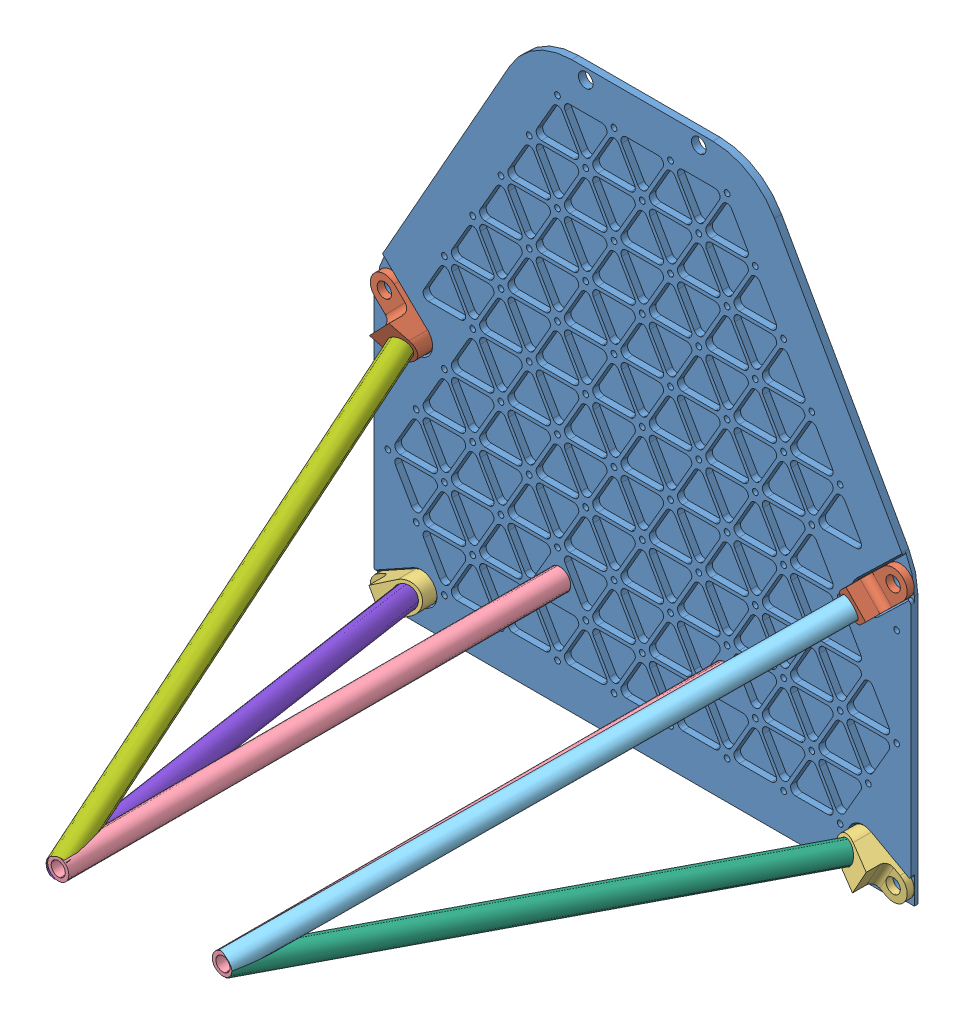
SolidWorks assembly Concept2_Simulation, configuration Default. Lengths in mm.
Overall size (493.12 512.57 459.07).
11 component instances, 8 part files, 30 mates.
Components (placement in the parent):
- Backplane_Simplifed-1: Backplane_Simplifed [Default] x (0 0 1) z (-1 0 0) size (6.35 508 482.6)
- Upper_Support_Mount-1: Upper_Support_Mount [Default] at (223.0175 237.3105 0) x (0.694489 -0.719504 0) z (-0.719504 -0.694489 0) size (25.4 25.4 61.27)
- Upper_Support_Mount-3: Upper_Support_Mount [Default] at (-205.3775 255.5859 0) x (0.694489 0.719504 0) z (0.719504 -0.694489 0) size (25.4 25.4 61.27)
- Lower_Support_Mount-1: Lower_Support_Mount [Default] at (223.4404 42.7827 0) x (-0.874551 0.484934 0) z (0 0 1) size (59.69 25.4 25.4)
- Chassis_Tube_1R-1: Chassis_Tube_1R [Default] at (0 111.125 -3.175) size (19.05 19.05 457.2)
- Chassis_Tube_2R-1: Chassis_Tube_2R [Default] at (0 111.125 -3.175) size (147.14 136.3 452.73)
- Chassis_Tube_3R-1: Chassis_Tube_3R [Default] at (0 111.125 -3.175) size (141.04 83.64 452.31)
- Chassis_Tube_1R-3: Chassis_Tube_1R [Default] at (-148 111.125 -3.175) size (19.05 19.05 457.2)
- Chassis_Tube_2L-1: Chassis_Tube_2L [Default] at (0 111.125 -3.175) size (147.14 136.3 452.73)
- Chassis_Tube_3L-1: Chassis_Tube_3L [Default] at (0 111.125 -3.175) size (141.04 85.18 452.31)
- Lower_Support_Mount-2: Lower_Support_Mount [Default] at (-211.1231 20.5691 0) x (0.874551 0.484934 0) z (0 0 1) size (59.69 25.4 25.4)
Mates (geometry in assembly coordinates):
- Coincident1: coincident aligned: plane of Backplane_Simplifed-1 through (0 0 0) normal (0 0 1)
- Coincident2: coincident anti-aligned: plane of Backplane_Simplifed-1 through (0 0 0) normal (-1 0 0)
- Coincident3: coincident aligned: plane of Backplane_Simplifed-1 through (0 0 0) normal (0 1 0)
- Concentric4: concentric anti-aligned: cylinder of Backplane_Simplifed-1 through (228.6 260.35 3.175) axis (0 0 -1) radius 6.5484; cylinder of Upper_Support_Mount-1 through (228.6 260.35 -6.7797) axis (0 0 1) radius 6.5484
- Parallel2: parallel anti-aligned: plane of Backplane_Simplifed-1 through (251.9603 264.9713 0) normal (-0.694489 0.719504 0); plane of Upper_Support_Mount-1 through (44.5113 65.0105 -3.175) normal (0.694489 -0.719504 0)
- Concentric5: concentric anti-aligned: cylinder of Backplane_Simplifed-1 through (228.6 25.4 3.175) axis (0 0 -1) radius 6.5484; cylinder of Lower_Support_Mount-1 through (228.6 25.4 -6.1235) axis (0 0 1) radius 6.5484
- Parallel3: parallel anti-aligned: plane of Backplane_Simplifed-1 through (204.8666 53.3087 0) normal (-0.484934 -0.874551 0); plane of Lower_Support_Mount-1 through (23.5606 153.6152 -3.175) normal (0.484934 0.874551 0)
- Concentric6: concentric anti-aligned: cylinder of Backplane_Simplifed-1 through (74 111.125 0) axis (0 0 1) radius 9.7234; cylinder of Chassis_Tube_1-1 through (74 111.125 454.025) axis (0 0 -1) radius 9.525
- Coincident8: coincident aligned: plane of Backplane_Simplifed-1 through (0 0 -3.175) normal (0 0 -1); plane of Chassis_Tube_1-1 through (74 111.125 -3.175) normal (0 0 -1)
- Concentric10: concentric anti-aligned: cylinder of Upper_Support_Mount-1 through (205.5695 238.1202 6.7766) axis (-0.272295 -0.262828 0.925622) radius 9.7234; cylinder of Chassis_Tube_2-1 through (74 111.125 454.025) axis (0.272295 0.262828 -0.925622) radius 9.525
- Coincident10: coincident anti-aligned: plane of Upper_Support_Mount-1 through (205.5695 238.1202 6.7766) normal (-0.272295 -0.262828 0.925622); plane of Chassis_Tube_2-1 through (205.5695 238.1202 6.7766) normal (0.272295 0.262828 -0.925622)
- Concentric11: concentric aligned: cylinder of Chassis_Tube_1-1 through (74 111.125 454.025) axis (0 0 -1) radius 9.525; cylinder of Chassis_Tube_2-1 through (74 111.125 454.025) axis (0 0 -1) radius 9.525
- Concentric12: concentric aligned: cylinder of Lower_Support_Mount-1 through (201.5042 40.4245 6.171) axis (-0.270717 0.150111 0.950883) radius 9.7234; cylinder of Chassis_Tube_3-1 through (204.1651 38.9491 -3.175) axis (-0.270717 0.150111 0.950883) radius 9.525
- Coincident11: coincident anti-aligned: plane of Lower_Support_Mount-1 through (201.5042 40.4245 6.171) normal (-0.270717 0.150111 0.950883); plane of Chassis_Tube_3-1 through (201.5042 40.4245 6.171) normal (0.270717 -0.150111 -0.950883)
- Concentric13: concentric aligned: cylinder of Chassis_Tube_2-1 through (74 111.125 454.025) axis (0.272295 0.262828 -0.925622) radius 9.525; cylinder of Chassis_Tube_3-1 through (74 111.125 454.025) axis (0.272295 0.262828 -0.925622) radius 9.525
- ProfileCenter1: profile center aligned: circle of Backplane_Simplifed-1; circle of Upper_Support_Mount-1
- Concentric14: concentric anti-aligned: cylinder of Backplane_Simplifed-1 through (-228.6 260.35 3.175) axis (0 0 -1) radius 6.5484; cylinder of Upper_Support_Mount-3 through (-228.6 260.35 -6.7797) axis (0 0 1) radius 6.5484
- Parallel5: parallel anti-aligned: plane of Backplane_Simplifed-1 through (-251.9603 264.9713 0) normal (0.694489 0.719504 0); plane of Upper_Support_Mount-3 through (-44.5113 65.0105 -3.175) normal (-0.694489 -0.719504 0)
- Concentric16: concentric anti-aligned: cylinder of Backplane_Simplifed-1 through (-74 111.125 0) axis (0 0 1) radius 9.7234; cylinder of Chassis_Tube_1-3 through (-74 111.125 454.025) axis (0 0 -1) radius 9.525
- Coincident16: coincident aligned: plane of Backplane_Simplifed-1 through (0 0 -3.175) normal (0 0 -1); plane of Chassis_Tube_1-3 through (-74 111.125 -3.175) normal (0 0 -1)
- Concentric17: concentric: cylinder of Upper_Support_Mount-3 through (-205.5695 238.1202 6.7766) axis (0.272295 -0.262828 0.925622) radius 9.7234; cylinder of Chassis_Tube_2L-1 through (-74 111.125 454.025) axis (-0.272295 0.262828 -0.925622) radius 9.525
- Coincident17: coincident: plane of Upper_Support_Mount-3 through (-205.5695 238.1202 6.7766) normal (0.272295 -0.262828 0.925622); plane of Chassis_Tube_2L-1 through (-205.5695 238.1202 6.7766) normal (-0.272295 0.262828 -0.925622)
- Tangent1: tangent: cylinder of Chassis_Tube_1R-3 through (-74 111.125 454.025) axis (0 0 -1) radius 9.525; cylinder of Chassis_Tube_2L-1 through (-74 111.125 454.025) axis (-0.612652 0.164772 -0.772986) radius 9.525
- Concentric19: concentric aligned: cylinder of Chassis_Tube_1R-3 through (-74 111.125 454.025) axis (0 0 -1) radius 9.525; cylinder of Chassis_Tube_3L-1 through (-74 111.125 454.025) axis (0 0 -1) radius 9.525
- Concentric20: concentric: cylinder of Chassis_Tube_2L-1 through (-74 111.125 454.025) axis (-0.272295 0.262828 -0.925622) radius 9.525; cylinder of Chassis_Tube_3L-1 through (-74 111.125 454.025) axis (-0.272295 0.262828 -0.925622) radius 9.525
- Concentric21: concentric anti-aligned: cylinder of Backplane_Simplifed-1 through (-228.6 25.4 3.175) axis (0 0 -1) radius 6.5484; cylinder of Lower_Support_Mount-2 through (-228.6 25.4 -6.1235) axis (0 0 1) radius 6.5484
- Parallel6: parallel anti-aligned: plane of Backplane_Simplifed-1 through (-204.8666 53.3087 0) normal (0.484934 -0.874551 0); plane of Lower_Support_Mount-2 through (-23.5606 153.6152 -3.175) normal (-0.484934 0.874551 0)
- Coincident19: coincident anti-aligned: plane of Chassis_Tube_3L-1 through (-201.5042 40.4245 6.171) normal (-0.270717 -0.150111 -0.950883); plane of Lower_Support_Mount-2 through (-201.5042 40.4245 6.171) normal (0.270717 0.150111 0.950883)
- Coincident20: coincident anti-aligned: plane of Backplane_Simplifed-1 through (-202.5576 235.213 0) normal (0 0 1); plane of Upper_Support_Mount-3 through (-184.8333 235.756 0) normal (0 0 -1)
- Concentric22: concentric aligned: cylinder of Chassis_Tube_2L-1 through (-204.1651 38.9491 -3.175) axis (0.270717 0.150111 0.950883) radius 9.525; cylinder of Chassis_Tube_3L-1 through (-204.1651 38.9491 -3.175) axis (0.270717 0.150111 0.950883) radius 9.525
